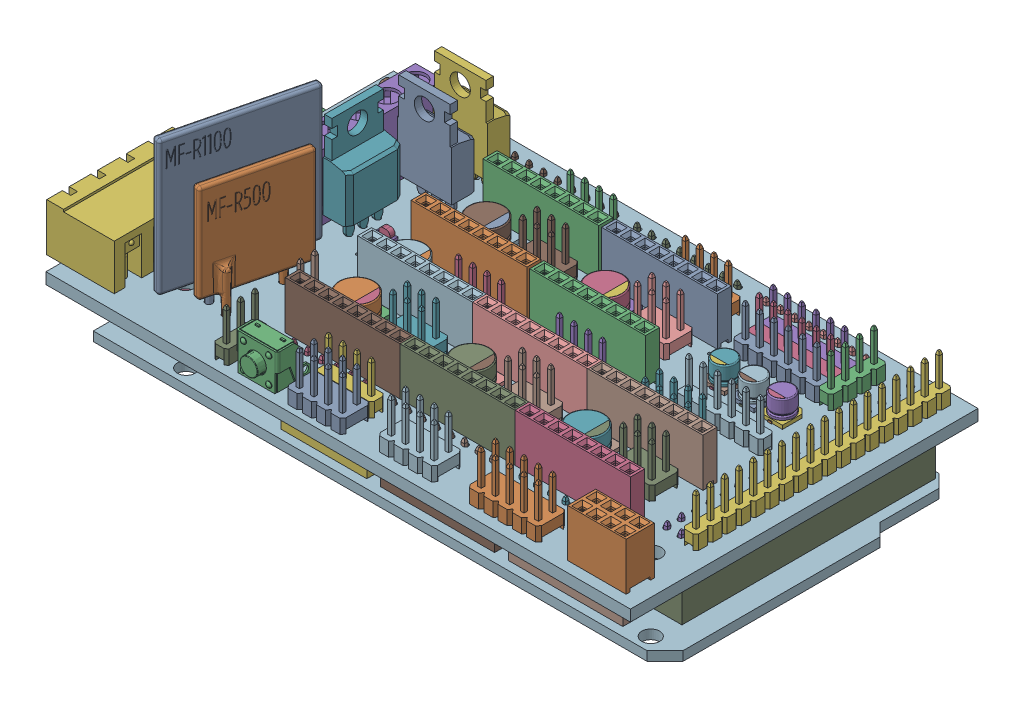
SolidWorks assembly 3-Arduino-Ramps Controller, configuration Default. Lengths in mm.
Overall size (110.35 43.64 61.76).
132 component instances, 43 part files, 3 mates.
Components (placement in the parent):
- 3-Arduino Mega Rev-3-1: 3-Arduino Mega Rev-3 [Default] at origin size (108.58 14.9 53.21)
  - 3-Part4-1: 3-Part4 [Default] at origin size (2.54 9.3 2.54)
  - 3-Part20-13: 3-Part20 [Default] at origin size (2.54 9.3 2.54)
  - 3-Part24-1: 3-Part24 [Default] at origin size (16.5 14.22 14.86)
  - 3-Part26-1: 3-Part26 [Default] at origin size (14.48 14.78 9.47)
  - 3-Part28-1: 3-Part28 [Default] at origin size (14 0.7 14)
  - 3-Part30-1: 3-Part30 [Default] at origin size (15.24 8.3 2.54)
  - 3-Part32-1: 3-Part32 [Default] at origin size (20.32 8.3 2.54)
  - 3-Part40-3: 3-Part40 [Default] at origin size (20.32 8.3 2.54)
  - 3-Part42-1: 3-Part42 [Default] at origin size (5.08 8.3 45.04)
  - 3-Part44-1: 3-Part44 [Default] at origin size (7.9 7.35 6.2)
  - 3-Part46-1: 3-Part46 [Default] at origin size (2.8 1.12 1.4)
  - 3-PCB-FIXED-1: 3-PCB-FIXED [Default] at (0.1155 -4.6912 4.2705) x (1 0 0) z (0 0 -1) size (101.6 1.65 53.21)
  - 3-Part4-7: 3-Part4 [Default] at (-2.54 0 0) size (2.54 9.3 2.54)
  - 3-Part4-8: 3-Part4 [Default] at (0 0 -2.54) size (2.54 9.3 2.54)
  - 3-Part4-9: 3-Part4 [Default] at (-2.54 0 -2.54) size (2.54 9.3 2.54)
  - 3-Part4-10: 3-Part4 [Default] at (0 0 -5.08) size (2.54 9.3 2.54)
  - 3-Part4-11: 3-Part4 [Default] at (-2.54 0 -5.08) size (2.54 9.3 2.54)
  - 3-Part20-14: 3-Part20 [Default] at (0 0 -2.54) size (2.54 9.3 2.54)
  - 3-Part20-15: 3-Part20 [Default] at (0 0 -5.08) size (2.54 9.3 2.54)
  - 3-Part20-16: 3-Part20 [Default] at (0 0 -7.62) size (2.54 9.3 2.54)
  - 3-Part32-6: 3-Part32 [Default] at (-22.77 0 0) size (20.32 8.3 2.54)
  - 3-Part32-7: 3-Part32 [Default] at (-45.54 0 0) size (20.32 8.3 2.54)
  - 3-Part40-4: 3-Part40 [Default] at (-22.77 0 0) size (20.32 8.3 2.54)
- 3-RAMPS1_4-1: 3-RAMPS1_4 [Default] at (3.7742 3.8684 8.77) size (106.38 37.63 61.76)
  - 3-RAMPS1_4-1: 3-RAMPS1_4 [Default] at (-38.4421 2.2803 -26.502) x (1 0 0) z (0 1 0) size (103.85 61.76 2)
  - 3-User Library-POWER MOSFET, NON-SURFACE-MOUNT-1: 3-User Library-POWER MOSFET, NON-SURFACE-MOUNT [Default] at (-31.1839 8.1207 -13.4695) x (-1 0 0) z (0 -1 0) size (9.65 4.5 28.38)
  - 3-female_header_a-bl254-dg-g08d-1: 3-female_header_a-bl254-dg-g08d [Default] at (41.0481 4.2584 25.6311) size (10.41 11.65 5)
  - 3-female_header_a-bl254-eg-g08d-2: 3-female_header_a-bl254-eg-g08d [Default] at (6.3865 4.2963 -6.1397) size (20.57 11.65 2.5)
  - 3-female_header_a-bl254-eg-g08d-19: 3-female_header_a-bl254-eg-g08d [Default] at (26.827 4.2963 16.9325) size (20.57 11.65 2.5)
  - 3-pin_header_aw254-dg-g36d-1: 3-pin_header_aw254-dg-g36d [Default] at (40.9113 2.2239 -7.3898) x (0 0 1) z (-1 0 0) size (45.72 11.5 5.08)
  - 3-pin_header_aw140-eg-g18d-1: 3-pin_header_aw140-eg-g18d [Default] at (44.7498 4.3175 -7.3949) x (0 0 -1) z (-1 0 0) size (45.62 11.2 2.5)
  - 3-pin_header_aw140-eg-g08d-1: 3-pin_header_aw140-eg-g08d [Default] at (28.1033 2.2803 19.4616) size (20.22 11.2 2.5)
  - 3-pin_header_aw140-eg-g08d-2: 3-pin_header_aw140-eg-g08d [Default] at (5.0609 2.2803 19.4616) size (20.22 11.2 2.5)
  - 3-pin_header_aw140-eg-g08d-3: 3-pin_header_aw140-eg-g08d [Default] at (-0.0426 2.2803 -29.0108) size (20.22 11.2 2.5)
  - 3-pin_header_aw140-eg-g08d-4: 3-pin_header_aw140-eg-g08d [Default] at (22.8713 2.2803 -29.0108) size (20.22 11.2 2.5)
  - 3-pin_header_aw140-eg-g08d-5: 3-pin_header_aw140-eg-g08d [Default] at (-21.773 2.2803 -29.0108) size (20.22 11.2 2.5)
  - 3-pin_header_aw140-eg-g06d-1: 3-pin_header_aw140-eg-g06d [Default] at (29.4382 4.2803 -6.1813) x (-1 0 0) z (0 0 1) size (15.14 11.2 2.5)
  - 3-pin_header_aw140-eg-g06d-2: 3-pin_header_aw140-eg-g06d [Default] at (26.2798 4.262 -19.3796) x (-1 0 0) z (0 0 1) size (15.14 11.2 2.5)
  - 3-pin_header_aw140-eg-g04d-1: 3-pin_header_aw140-eg-g04d [Default] at (8.4073 4.2803 -24.0519) x (-1 0 0) z (0 0 1) size (10.06 11.2 2.5)
  - 3-pin_header_aw140-eg-g04d-2: 3-pin_header_aw140-eg-g04d [Default] at (-12.021 4.262 -24.0519) x (-1 0 0) z (0 0 1) size (10.06 11.2 2.5)
  - 3-pin_header_aw140-eg-g04d-3: 3-pin_header_aw140-eg-g04d [Default] at (-8.9039 4.262 -1.0355) x (-1 0 0) z (0 0 1) size (10.06 11.2 2.5)
  - 3-pin_header_aw140-eg-g04d-4: 3-pin_header_aw140-eg-g04d [Default] at (9.0685 4.262 -1.0355) x (-1 0 0) z (0 0 1) size (10.06 11.2 2.5)
  - 3-pin_header_aw140-eg-g04d-5: 3-pin_header_aw140-eg-g04d [Default] at (-8.3709 4.2803 22.5944) x (-1 0 0) z (0 0 1) size (10.06 11.2 2.5)
  - 3-pin_header_aw254-dg-g06d-1: 3-pin_header_aw254-dg-g06d [Default] at (-10.2573 4.2803 9.2323) x (-1 0 0) z (0 0 1) size (7.62 11.5 5.08)
  - 3-pin_header_aw254-dg-g06d-2: 3-pin_header_aw254-dg-g06d [Default] at (10.1683 4.262 9.2323) x (-1 0 0) z (0 0 1) size (7.62 11.5 5.08)
  - 3-pin_header_aw254-dg-g06d-3: 3-pin_header_aw254-dg-g06d [Default] at (30.6527 4.262 9.2323) x (-1 0 0) z (0 0 1) size (7.62 11.5 5.08)
  - 3-pin_header_aw254-dg-g06d-4: 3-pin_header_aw254-dg-g06d [Default] at (10.1683 4.262 -13.7827) x (-1 0 0) z (0 0 1) size (7.62 11.5 5.08)
  - 3-pin_header_aw254-dg-g06d-5: 3-pin_header_aw254-dg-g06d [Default] at (-10.2204 4.262 -13.7827) x (-1 0 0) z (0 0 1) size (7.62 11.5 5.08)
  - 3-pin_header_aw254-dg-g08d-1: 3-pin_header_aw254-dg-g08d [Default] at (7.0775 4.2803 25.6017) x (-1 0 0) z (0 0 1) size (10.16 11.5 5.08)
  - 3-pin_header_aw254-dg-g08d-2: 3-pin_header_aw254-dg-g08d [Default] at (-8.3884 4.2803 26.4286) x (-1 0 0) z (0 0 1) size (10.16 11.5 5.08)
  - 3-pin_header_aw254-dg-g10d-1: 3-pin_header_aw254-dg-g10d [Default] at (24.3252 4.2803 25.6162) x (-1 0 0) z (0 0 1) size (12.7 11.5 5.08)
  - 3-pin_header_aw140-eg-g04d-6: 3-pin_header_aw140-eg-g04d [Default] at (35.1498 4.262 -23.186) x (0 0 -1) z (-1 0 0) size (10.06 11.2 2.5)
  - 3-pin_header_aw140-eg-g06d-8: 3-pin_header_aw140-eg-g06d [Default] at (-15.2568 2.2803 19.3514) size (15.14 11.2 2.5)
  - 3-terminal_blocks_a-tb500-to06-1: 3-terminal_blocks_a-tb500-to06 [Default] at (-37.528 4.2803 -9.8658) x (0 0 1) z (-1 0 0) size (30.6 13.8 8.3)
  - 3-terminal_blocks_a-tb508-oq04ch-1: 3-terminal_blocks_a-tb508-oq04ch [Default] at (-57.4712 4.2803 16.3679) x (0 0 1) z (-1 0 0) size (22.32 12.5 12)
  - 3-pin_header_aw254-dg-g08d-3: 3-pin_header_aw254-dg-g08d [Default] at (26.8817 4.262 0.2918) x (-1 0 0) z (0 0 1) size (10.16 11.5 5.08)
  - 3-pin_header_aw140-eg-g02d-1: 3-pin_header_aw140-eg-g02d [Default] at (-26.0896 4.2803 12.3888) x (0 0 1) z (1 0 0) size (4.98 11.2 2.5)
  - 3-pin_header_aw140-eg-g03d-1: 3-pin_header_aw140-eg-g03d [Default] at (-25.5036 4.2803 24.8649) x (0 0 1) z (1 0 0) size (7.52 11.2 2.5)
  - 3-User Library-CAPSMD6_3x3_9-1: 3-User Library-CAPSMD6_3x3_9 [Default] at (-23.4034 4.2803 -13.8521) x (0 0 -1) z (0 1 0) size (6.6 7 3.91)
    - 3-User Library-CAPSMD6_3x3_9_CAP003-1: 3-User Library-CAPSMD6_3x3_9_CAP003 [Default] at origin size (0.65 2.6 0.32)
    - 3-User Library-CAPSMD6_3x3_9_CAP-1: 3-User Library-CAPSMD6_3x3_9_CAP [Default] at origin size (6.3 6.3 3.26)
    - 3-User Library-CAPSMD6_3x3_9_CAP001-1: 3-User Library-CAPSMD6_3x3_9_CAP001 [Default] at origin size (6.6 6.6 0.64)
    - 3-User Library-CAPSMD6_3x3_9_CAP002-1: 3-User Library-CAPSMD6_3x3_9_CAP002 [Default] at origin size (5.11 1.47 0.01)
    - 3-User Library-CAPSMD6_3x3_9_CAP004-1: 3-User Library-CAPSMD6_3x3_9_CAP004 [Default] at origin size (0.65 2.6 0.32)
  - 3-User Library-CAPSMD6_3x3_9-2: 3-User Library-CAPSMD6_3x3_9 [Default] at (-2.2688 4.2803 -13.8521) x (0 0 -1) z (0 1 0) size (6.6 7 3.91)
    - 3-User Library-CAPSMD6_3x3_9_CAP003-1: 3-User Library-CAPSMD6_3x3_9_CAP003 [Default] at origin size (0.65 2.6 0.32)
    - 3-User Library-CAPSMD6_3x3_9_CAP-1: 3-User Library-CAPSMD6_3x3_9_CAP [Default] at origin size (6.3 6.3 3.26)
    - 3-User Library-CAPSMD6_3x3_9_CAP001-1: 3-User Library-CAPSMD6_3x3_9_CAP001 [Default] at origin size (6.6 6.6 0.64)
    - 3-User Library-CAPSMD6_3x3_9_CAP002-1: 3-User Library-CAPSMD6_3x3_9_CAP002 [Default] at origin size (5.11 1.47 0.01)
    - 3-User Library-CAPSMD6_3x3_9_CAP004-1: 3-User Library-CAPSMD6_3x3_9_CAP004 [Default] at origin size (0.65 2.6 0.32)
  - 3-User Library-CAPSMD6_3x3_9-3: 3-User Library-CAPSMD6_3x3_9 [Default] at (-2.8787 4.2803 9.2865) x (0 0 -1) z (0 1 0) size (6.6 7 3.91)
    - 3-User Library-CAPSMD6_3x3_9_CAP003-1: 3-User Library-CAPSMD6_3x3_9_CAP003 [Default] at origin size (0.65 2.6 0.32)
    - 3-User Library-CAPSMD6_3x3_9_CAP-1: 3-User Library-CAPSMD6_3x3_9_CAP [Default] at origin size (6.3 6.3 3.26)
    - 3-User Library-CAPSMD6_3x3_9_CAP001-1: 3-User Library-CAPSMD6_3x3_9_CAP001 [Default] at origin size (6.6 6.6 0.64)
    - 3-User Library-CAPSMD6_3x3_9_CAP002-1: 3-User Library-CAPSMD6_3x3_9_CAP002 [Default] at origin size (5.11 1.47 0.01)
    - 3-User Library-CAPSMD6_3x3_9_CAP004-1: 3-User Library-CAPSMD6_3x3_9_CAP004 [Default] at origin size (0.65 2.6 0.32)
  - 3-User Library-CAPSMD6_3x3_9-4: 3-User Library-CAPSMD6_3x3_9 [Default] at (-23.2996 4.2803 9.2865) x (0 0 -1) z (0 1 0) size (6.6 7 3.91)
    - 3-User Library-CAPSMD6_3x3_9_CAP003-1: 3-User Library-CAPSMD6_3x3_9_CAP003 [Default] at origin size (0.65 2.6 0.32)
    - 3-User Library-CAPSMD6_3x3_9_CAP-1: 3-User Library-CAPSMD6_3x3_9_CAP [Default] at origin size (6.3 6.3 3.26)
    - 3-User Library-CAPSMD6_3x3_9_CAP001-1: 3-User Library-CAPSMD6_3x3_9_CAP001 [Default] at origin size (6.6 6.6 0.64)
    - 3-User Library-CAPSMD6_3x3_9_CAP002-1: 3-User Library-CAPSMD6_3x3_9_CAP002 [Default] at origin size (5.11 1.47 0.01)
    - 3-User Library-CAPSMD6_3x3_9_CAP004-1: 3-User Library-CAPSMD6_3x3_9_CAP004 [Default] at origin size (0.65 2.6 0.32)
  - 3-User Library-CAPSMD6_3x3_9-5: 3-User Library-CAPSMD6_3x3_9 [Default] at (17.5196 4.2803 9.2865) x (0 0 -1) z (0 1 0) size (6.6 7 3.91)
    - 3-User Library-CAPSMD6_3x3_9_CAP003-1: 3-User Library-CAPSMD6_3x3_9_CAP003 [Default] at origin size (0.65 2.6 0.32)
    - 3-User Library-CAPSMD6_3x3_9_CAP-1: 3-User Library-CAPSMD6_3x3_9_CAP [Default] at origin size (6.3 6.3 3.26)
    - 3-User Library-CAPSMD6_3x3_9_CAP001-1: 3-User Library-CAPSMD6_3x3_9_CAP001 [Default] at origin size (6.6 6.6 0.64)
    - 3-User Library-CAPSMD6_3x3_9_CAP002-1: 3-User Library-CAPSMD6_3x3_9_CAP002 [Default] at origin size (5.11 1.47 0.01)
    - 3-User Library-CAPSMD6_3x3_9_CAP004-1: 3-User Library-CAPSMD6_3x3_9_CAP004 [Default] at origin size (0.65 2.6 0.32)
  - 3-User Library-CAPSMD6_3x3_9-6: 3-User Library-CAPSMD6_3x3_9 [Default] at (-24.6073 4.2803 -1.0117) x (0 0 -1) z (0 1 0) size (6.6 7 3.91)
    - 3-User Library-CAPSMD6_3x3_9_CAP003-1: 3-User Library-CAPSMD6_3x3_9_CAP003 [Default] at origin size (0.65 2.6 0.32)
    - 3-User Library-CAPSMD6_3x3_9_CAP-1: 3-User Library-CAPSMD6_3x3_9_CAP [Default] at origin size (6.3 6.3 3.26)
    - 3-User Library-CAPSMD6_3x3_9_CAP001-1: 3-User Library-CAPSMD6_3x3_9_CAP001 [Default] at origin size (6.6 6.6 0.64)
    - 3-User Library-CAPSMD6_3x3_9_CAP002-1: 3-User Library-CAPSMD6_3x3_9_CAP002 [Default] at origin size (5.11 1.47 0.01)
    - 3-User Library-CAPSMD6_3x3_9_CAP004-1: 3-User Library-CAPSMD6_3x3_9_CAP004 [Default] at origin size (0.65 2.6 0.32)
  - 3-User Library-CAPSMD4x3_9-1: 3-User Library-CAPSMD4x3_9 [Default] at (22.2937 4.2803 -15.1178) x (1 0 0) z (0 1 0) size (4.3 4.6 3.91)
    - 3-User Library-CAPSMD4x3_9_CAPSMD4x3_9003-1: 3-User Library-CAPSMD4x3_9_CAPSMD4x3_9003 [Default] at origin size (0.65 1.8 0.32)
    - 3-User Library-CAPSMD4x3_9_CAPSMD4x3_9004-1: 3-User Library-CAPSMD4x3_9_CAPSMD4x3_9004 [Default] at origin size (0.65 1.8 0.32)
    - 3-User Library-CAPSMD4x3_9_CAPSMD4x3_9002-1: 3-User Library-CAPSMD4x3_9_CAPSMD4x3_9002 [Default] at origin size (3.12 0.9 0.01)
    - 3-User Library-CAPSMD4x3_9_CAPSMD4x3_9001-1: 3-User Library-CAPSMD4x3_9_CAPSMD4x3_9001 [Default] at origin size (4 4 3.26)
    - 3-User Library-CAPSMD4x3_9_CAPSMD4x3_9-1: 3-User Library-CAPSMD4x3_9_CAPSMD4x3_9 [Default] at origin size (4.3 4.3 0.64)
  - 3-User Library-CAPSMD4x3_9-2: 3-User Library-CAPSMD4x3_9 [Default] at (27.5508 4.2803 -15.1178) x (1 0 0) z (0 1 0) size (4.3 4.6 3.91)
    - 3-User Library-CAPSMD4x3_9_CAPSMD4x3_9003-1: 3-User Library-CAPSMD4x3_9_CAPSMD4x3_9003 [Default] at origin size (0.65 1.8 0.32)
    - 3-User Library-CAPSMD4x3_9_CAPSMD4x3_9004-1: 3-User Library-CAPSMD4x3_9_CAPSMD4x3_9004 [Default] at origin size (0.65 1.8 0.32)
    - 3-User Library-CAPSMD4x3_9_CAPSMD4x3_9002-1: 3-User Library-CAPSMD4x3_9_CAPSMD4x3_9002 [Default] at origin size (3.12 0.9 0.01)
    - 3-User Library-CAPSMD4x3_9_CAPSMD4x3_9001-1: 3-User Library-CAPSMD4x3_9_CAPSMD4x3_9001 [Default] at origin size (4 4 3.26)
    - 3-User Library-CAPSMD4x3_9_CAPSMD4x3_9-1: 3-User Library-CAPSMD4x3_9_CAPSMD4x3_9 [Default] at origin size (4.3 4.3 0.64)
  - 3-User Library-CAPSMD4x3_9-3: 3-User Library-CAPSMD4x3_9 [Default] at (32.6212 4.2803 -15.1178) x (1 0 0) z (0 1 0) size (4.3 4.6 3.91)
    - 3-User Library-CAPSMD4x3_9_CAPSMD4x3_9003-1: 3-User Library-CAPSMD4x3_9_CAPSMD4x3_9003 [Default] at origin size (0.65 1.8 0.32)
    - 3-User Library-CAPSMD4x3_9_CAPSMD4x3_9004-1: 3-User Library-CAPSMD4x3_9_CAPSMD4x3_9004 [Default] at origin size (0.65 1.8 0.32)
    - 3-User Library-CAPSMD4x3_9_CAPSMD4x3_9002-1: 3-User Library-CAPSMD4x3_9_CAPSMD4x3_9002 [Default] at origin size (3.12 0.9 0.01)
    - 3-User Library-CAPSMD4x3_9_CAPSMD4x3_9001-1: 3-User Library-CAPSMD4x3_9_CAPSMD4x3_9001 [Default] at origin size (4 4 3.26)
    - 3-User Library-CAPSMD4x3_9_CAPSMD4x3_9-1: 3-User Library-CAPSMD4x3_9_CAPSMD4x3_9 [Default] at origin size (4.3 4.3 0.64)
  - 3-User Library-APA3010GCCK_GREEN-1: 3-User Library-APA3010GCCK_GREEN [Default] at (-34.2243 4.3303 -27.7242) x (0 0 1) z (-1 0 0) size (3 2 1)
  - 3-User Library-APA3010GCCK_RED-1: 3-User Library-APA3010GCCK_RED [Default] at (-49.6191 4.3303 -27.7242) x (0 0 1) z (-1 0 0) size (3 2 1)
  - 3-User Library-APA3010GCCK_RED-2: 3-User Library-APA3010GCCK_RED [Default] at (-52.1602 4.3303 -27.7242) x (0 0 1) z (-1 0 0) size (3 2 1)
  - 3-User Library-MF-R1100___ _________-1: 3-User Library-MF-R1100___ _________ [Default] at (-35.7942 -0.3428 15.0699) x (0 0 -1) z (0 -1 0) size (23.64 7.06 35.7)
  - 3-User Library-MF-R500___ _________-1: 3-User Library-MF-R500___ _________ [Default] at (-32.5552 -0.5896 15.3075) x (0 0 -1) z (0 -1 0) size (17.04 5.43 29.1)
  - 3-User Library-SWITCH, TACTILE, RIGHT ANGLE, 12VDC, 50MA, 6_85MM ACTUATOR, WEALTH METAL TC-0244Z-1: 3-User Library-SWITCH, TACTILE, RIGHT ANGLE, 12VDC, 50MA, 6_85MM ACTUATOR, WEALTH METAL TC-0244Z [Default] at (-19.0613 3.9803 23.5512) size (7.4 11 8)
  - 3-User Library-APA3010GCCK_RED-3: 3-User Library-APA3010GCCK_RED [Default] at (-29.5185 4.3303 -5.1301) size (3 2 1)
  - 3-User Library-POWER MOSFET, NON-SURFACE-MOUNT-2: 3-User Library-POWER MOSFET, NON-SURFACE-MOUNT [Default] at (-31.3941 8.433 -20.0341) x (-1 0 0) z (0 -1 0) size (9.65 4.5 28.38)
  - 3-User Library-POWER MOSFET, NON-SURFACE-MOUNT-3: 3-User Library-POWER MOSFET, NON-SURFACE-MOUNT [Default] at (-36.1067 8.2823 -5.2135) x (0 0 -1) z (0 -1 0) size (9.65 4.5 28.38)
  - 3-female_header_a-bl254-eg-g08d-20: 3-female_header_a-bl254-eg-g08d [Default] at (26.827 4.2963 4.0825) size (20.57 11.65 2.5)
  - 3-female_header_a-bl254-eg-g08d-21: 3-female_header_a-bl254-eg-g08d [Default] at (6.417 4.2963 16.9325) size (20.57 11.65 2.5)
  - 3-female_header_a-bl254-eg-g08d-22: 3-female_header_a-bl254-eg-g08d [Default] at (6.417 4.2963 4.0825) size (20.57 11.65 2.5)
  - 3-female_header_a-bl254-eg-g08d-23: 3-female_header_a-bl254-eg-g08d [Default] at (-13.993 4.2963 16.9325) size (20.57 11.65 2.5)
  - 3-female_header_a-bl254-eg-g08d-24: 3-female_header_a-bl254-eg-g08d [Default] at (-13.993 4.2963 4.0825) size (20.57 11.65 2.5)
  - 3-female_header_a-bl254-eg-g08d-16: 3-female_header_a-bl254-eg-g08d [Default] at (6.3865 4.2963 -18.9097) size (20.57 11.65 2.5)
  - 3-female_header_a-bl254-eg-g08d-17: 3-female_header_a-bl254-eg-g08d [Default] at (-14.6935 4.2963 -6.1397) size (20.57 11.65 2.5)
  - 3-female_header_a-bl254-eg-g08d-18: 3-female_header_a-bl254-eg-g08d [Default] at (-14.6935 4.2963 -18.9097) size (20.57 11.65 2.5)
  - 3-pin_header_aw140-eg-g06d-6: 3-pin_header_aw140-eg-g06d [Default] at (26.2798 4.262 -21.8496) x (-1 0 0) z (0 0 1) size (15.14 11.2 2.5)
  - 3-pin_header_aw140-eg-g06d-7: 3-pin_header_aw140-eg-g06d [Default] at (26.2798 4.262 -24.3196) x (-1 0 0) z (0 0 1) size (15.14 11.2 2.5)
Mates (geometry in assembly coordinates):
- Coincident1: coincident: plane of ? through (41.0875 -0.3912 28.5516) normal (-1 0 0); plane of 3-RAMPS1_4-1/3-pin_header_aw140-eg-g08d-1 through (41.0875 -1.5054 27.7316) normal (1 0 0)
- Coincident2: coincident: plane of ? through (41.0875 -0.3912 28.5516) normal (0 0 -1); plane of 3-RAMPS1_4-1/3-pin_header_aw140-eg-g08d-1 through (41.2675 -1.5054 28.5516) normal (0 0 1)
- Coincident3: coincident: plane of ? through (21.5375 3.6088 29.3216) normal (0 1 0); plane of 3-RAMPS1_4-1/3-pin_header_aw140-eg-g08d-1 through (24.1575 3.6088 29.4816) normal (0 -1 0)
